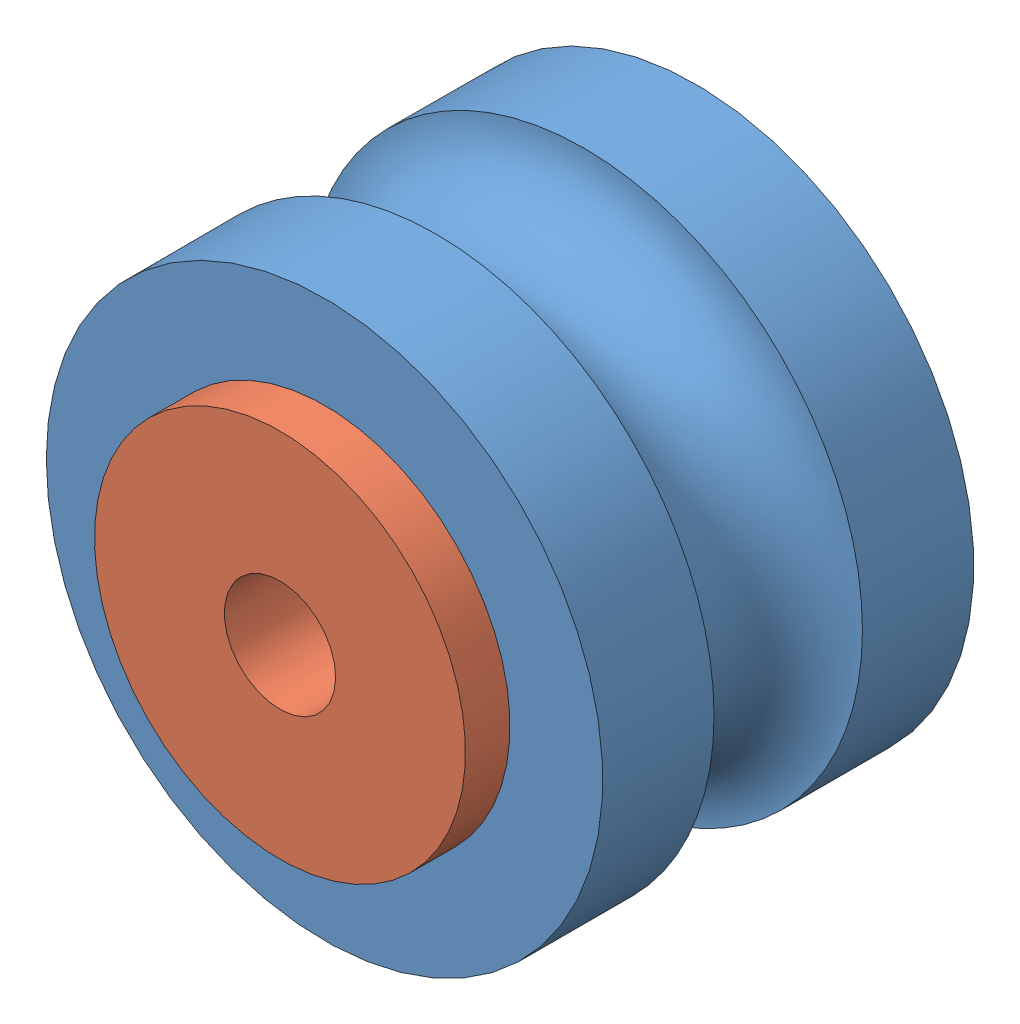
SolidWorks assembly Assem bearing palm, configuration Default. Lengths in mm.
Overall size (7.5 7.5 6.2).
3 component instances, 2 part files, 4 mates.
Components (placement in the parent):
- bearing palm-1: bearing palm [Default] at (1.9958 5.2426 5.2783) size (7.5 7.5 5)
- bearing 1.5-4-5-2-1: bearing 1.5-4-5-2 [Default] at (1.9958 5.2426 4.1783) x (0.981869 0.189559 0) z (-0.189559 0.981869 0) size (5 2 5)
- bearing 1.5-4-5-2-2: bearing 1.5-4-5-2 [Default] at (1.9958 5.2426 6.3783) x (-0.623007 -0.782216 0) z (-0.782216 0.623007 0) size (5 2 5)
Mates (geometry in assembly coordinates):
- Concentric1: concentric: cylinder of assembly; cylinder of assembly; cylinder of bearing palm-1 through (1.9958 5.2426 7.7783) axis (0 0 -1) radius 2.05; cylinder of bearing 1.5-4-5-2-1 through (1.9958 5.2426 2.1783) axis (0 0 1) radius 2
- Coincident1: coincident: plane of assembly; plane of assembly; plane of bearing palm-1 through (1.9958 5.2426 2.7783) normal (0 0 -1); plane of bearing 1.5-4-5-2-1 through (1.9958 5.2426 2.7783) normal (0 0 1)
- Concentric2: concentric: cylinder of assembly; cylinder of assembly; cylinder of bearing palm-1 through (1.9958 5.2426 7.7783) axis (0 0 -1) radius 2.05; cylinder of bearing 1.5-4-5-2-2 through (1.9958 5.2426 8.3783) axis (0 0 -1) radius 2
- Coincident2: coincident: plane of assembly; plane of assembly; plane of bearing palm-1 through (1.9958 5.2426 7.7783) normal (0 0 1); plane of bearing 1.5-4-5-2-2 through (1.9958 5.2426 7.7783) normal (0 0 -1)
